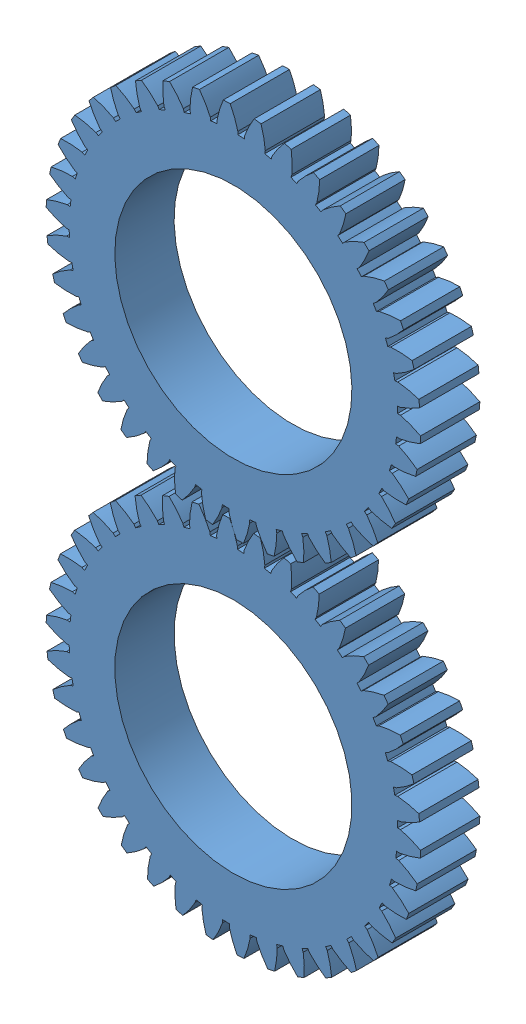
SolidWorks assembly Gear System, configuration Default. Lengths in mm.
Overall size (112.49 184 12.7).
2 component instances, 1 part files, 5 mates.
Components (placement in the parent):
- Gear Design Tutorial-1: Gear Design Tutorial [Default] at (0 9.062 0) x (0.947724 0.319093 0) z (0 0 1) size (80.19 80.19 12.7)
- Gear Design Tutorial-2: Gear Design Tutorial [Default] at (0 -67.9 0) x (0.791148 0.611625 0) z (0 0 1) size (80.19 80.19 12.7)
Mates (geometry in assembly coordinates):
- Distance1: distance = 76.962 mm: axis of Gear Design Tutorial-1 through (0 9.062 12.7) axis (0 0 -1); axis of Gear Design Tutorial-2 through (0 -67.9 12.7) axis (0 0 -1)
- Coincident2: coincident: plane of Gear Design Tutorial-1 through (0 9.062 12.7) normal (0 0 1); plane of Gear Design Tutorial-2 through (0 -67.9 12.7) normal (0 0 1)
- Coincident3: coincident: axis of Gear Design Tutorial-2 through (0 -67.9 12.7) axis (0 0 -1); plane of assembly
- Coincident4: coincident: plane of Gear Design Tutorial-1 through (0 9.062 0) normal (0 0 1); plane of assembly through (0 0 0) normal (0 0 1)
- Coincident8: coincident: axis of Gear Design Tutorial-1 through (0 9.062 12.7) axis (0 0 -1); plane of assembly
